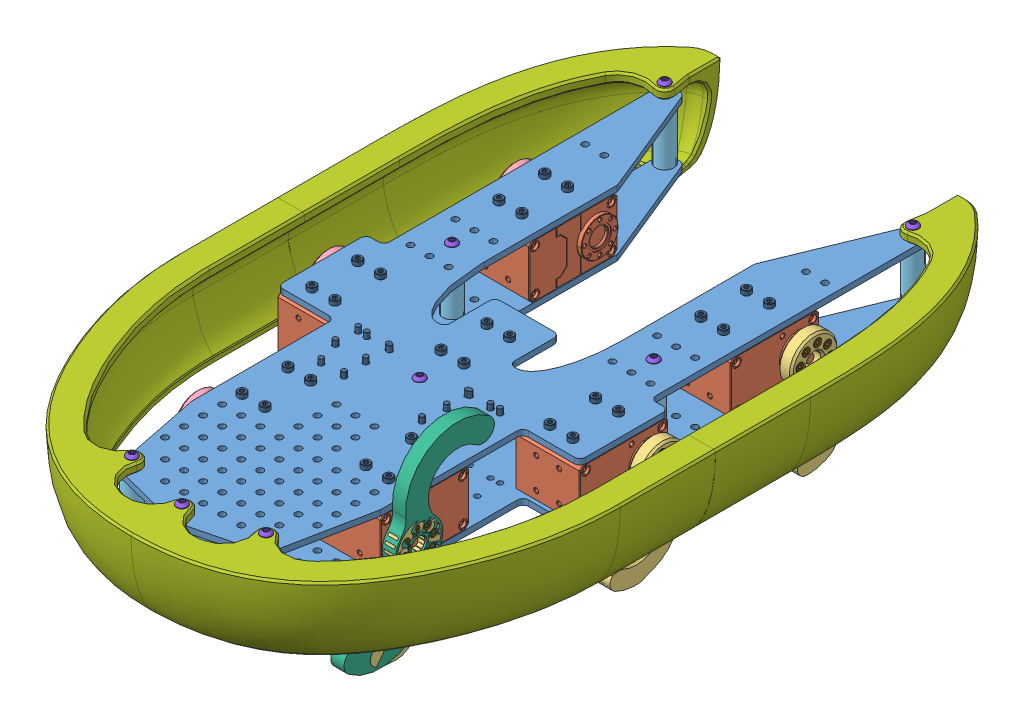
SolidWorks assembly 0100-A-Drive Base Flat, configuration Default. Lengths in mm.
Overall size (299.55 79.42 397.77).
179 component instances, 12 part files, 60 mates.
Components (placement in the parent):
- 0100-P-01-Frame Flat-2: 0100-P-01-Frame Flat [Default] at origin size (168 3.15 328.59)
- DYNAMIXEL XM,H-430-1: DYNAMIXEL XM,H-430 [Default] at (53 14.25 -88.75) x (0 -1 0) z (1 0 0) size (28.5 46.5 42.4)
- 0100-P-02-Leg-2: 0100-P-02-Leg [Default] at (51.5 14.25 98.75) x (1 0 0) z (0 0.528293 0.849062) size (7.78 62.2 37.5)
- DYNAMIXEL XM,H-430-3: DYNAMIXEL XM,H-430 [Default] at (62.5 14.25 0) x (0 -1 0) z (1 0 0) size (28.5 46.5 42.4)
- 0100-P-02-Leg-3: 0100-P-02-Leg [Default] at (81.5 14.25 0) x (1 0 0) z (0 0.588908 0.8082) size (7.78 62.2 37.5)
- DYNAMIXEL XM,H-430-4: DYNAMIXEL XM,H-430 [Default] at (-53 14.25 -88.75) x (0 1 0) z (-1 0 0) size (28.5 46.5 42.4)
- Mirror0100-P-02-Leg-4: Mirror0100-P-02-Leg [Default] at (-81.5 14.25 0) x (-1 0 0) z (0 -0.588908 -0.8082) size (7.78 62.2 37.5)
- DYNAMIXEL XM,H-430-6: DYNAMIXEL XM,H-430 [Default] at (-62.5 14.25 0) x (0 1 0) z (-1 0 0) size (28.5 46.5 42.4)
- Mirror0100-P-02-Leg-5: Mirror0100-P-02-Leg [Default] at (-51.5 14.25 98.75) x (-1 0 0) z (0 -0.528293 -0.849062) size (7.78 62.2 37.5)
- 0100-P-02-Leg-8: 0100-P-02-Leg [Default] at (72 14.25 -88.75) x (1 0 0) z (0 0.172625 0.984988) size (7.78 62.2 37.5)
- Mirror0100-P-02-Leg-9: Mirror0100-P-02-Leg [Default] at (-72 14.25 -88.75) x (-1 0 0) z (0 -0.172625 -0.984988) size (7.78 62.2 37.5)
- DYNAMIXEL XM,H-430-7: DYNAMIXEL XM,H-430 [Default] at (32.5 14.25 98.75) x (0 1 0) z (1 0 0) size (28.5 46.5 42.4)
- DYNAMIXEL XM,H-430-8: DYNAMIXEL XM,H-430 [Default] at (-32.5 14.25 98.75) x (0 -1 0) z (-1 0 0) size (28.5 46.5 42.4)
- 0100-P-01-Frame Flat-3: 0100-P-01-Frame Flat [Default] at (0 31.5 0) size (168 3.15 328.59)
- 0100-P-03-Frame Spacer-1: 0100-P-03-Frame Spacer [Default] at (0 14.25 164.8423) size (9.53 28.5 9.53)
- 0100-P-03-Frame Spacer-4: 0100-P-03-Frame Spacer [Default] at (-53 14.25 -30) size (9.53 28.5 9.53)
- 0100-P-03-Frame Spacer-5: 0100-P-03-Frame Spacer [Default] at (53 14.25 -30) size (9.53 28.5 9.53)
- 0100-P-03-Frame Spacer-8: 0100-P-03-Frame Spacer [Default] at (0 14.25 39.9478) size (9.53 28.5 9.53)
- 0100-P-02-Leg S-1: 0100-P-02-Leg S [Default] at (51.5 14.25 98.75) x (1 0 0) z (0 -0.739993 -0.672614) size (7 109.35 55) (hidden)
- 0100-P-03-Frame Spacer-9: 0100-P-03-Frame Spacer [Default] at (-35.2156 14.25 155.9269) size (9.53 28.5 9.53)
- 0100-P-03-Frame Spacer-10: 0100-P-03-Frame Spacer [Default] at (35.2156 14.25 155.9269) size (9.53 28.5 9.53)
- part1^0100-a-drive base flat-1: part1^0100-a-drive base flat [Default] at origin (suppressed, hidden, virtual)
- 0100-P-03-Frame Spacer-11: 0100-P-03-Frame Spacer [Default] at (-65.2375 14.25 -153.9875) size (9.53 28.5 9.53)
- 0100-P-03-Frame Spacer-12: 0100-P-03-Frame Spacer [Default] at (65.2375 14.25 -153.9875) size (9.53 28.5 9.53)
- 0100-P-04-Bottom Shell-1: 0100-P-04-Bottom Shell [Default] at origin size (299.55 50.12 397.77)
- 92095A168_Button Head Hex Drive Screw-1: 92095A168_Button Head Hex Drive Screw [92095A168] at (35.2156 -8.4212 155.9269) x (-0.18378 0 0.982967) z (0 -1 0) size (5.7 5.7 15.77)
- 92095A168_Button Head Hex Drive Screw-3: 92095A168_Button Head Hex Drive Screw [92095A168] at (0 -8.4212 164.8423) x (-0.18378 0 0.982967) z (0 -1 0) size (5.7 5.7 15.77)
- 92095A168_Button Head Hex Drive Screw-8: 92095A168_Button Head Hex Drive Screw [92095A168] at (0 38.15 164.8423) x (0.861075 0 -0.508478) z (0 1 0) size (5.7 5.7 15.77)
- 92095A168_Button Head Hex Drive Screw-18: 92095A168_Button Head Hex Drive Screw [92095A168] at (65.2375 -8.4212 -153.9875) x (0.722393 0 0.691483) z (0 -1 0) size (5.7 5.7 15.77)
- 92095A168_Button Head Hex Drive Screw-22: 92095A168_Button Head Hex Drive Screw [92095A168] at (35.2156 38.15 155.9269) x (0.749821 0 -0.661641) z (0 1 0) size (5.7 5.7 15.77)
- 92095A168_Button Head Hex Drive Screw-25: 92095A168_Button Head Hex Drive Screw [92095A168] at (65.2375 38.15 -153.9875) x (0.152162 0 -0.988356) z (0 1 0) size (5.7 5.7 15.77)
- 92095A168_Button Head Hex Drive Screw-28: 92095A168_Button Head Hex Drive Screw [92095A168] at (0 33.15 39.9478) x (0.426776 0 -0.904358) z (0 1 0) size (5.7 5.7 15.77)
- 92095A168_Button Head Hex Drive Screw-32: 92095A168_Button Head Hex Drive Screw [92095A168] at (53 33.15 -30) x (0.248698 0 -0.968581) z (0 1 0) size (5.7 5.7 15.77)
- 92095A168_Button Head Hex Drive Screw-34: 92095A168_Button Head Hex Drive Screw [92095A168] at (0 -4.65 39.9478) x (0.231386 0 0.972862) z (0 -1 0) size (5.7 5.7 15.77)
- 92095A168_Button Head Hex Drive Screw-36: 92095A168_Button Head Hex Drive Screw [92095A168] at (53 -4.65 -30) x (-0.704193 0 0.710008) z (0 -1 0) size (5.7 5.7 15.77)
- 92095A168_Button Head Hex Drive Screw-38: 92095A168_Button Head Hex Drive Screw [92095A168] at (-53 33.15 -30) x (0.248698 0 0.968581) z (0 1 0) size (5.7 5.7 15.77)
- 92095A168_Button Head Hex Drive Screw-39: 92095A168_Button Head Hex Drive Screw [92095A168] at (-65.2375 38.15 -153.9875) x (0.152162 0 0.988356) z (0 1 0) size (5.7 5.7 15.77)
- 92095A168_Button Head Hex Drive Screw-40: 92095A168_Button Head Hex Drive Screw [92095A168] at (-65.2375 -8.4212 -153.9875) x (-0.722393 0 0.691483) z (0 -1 0) size (5.7 5.7 15.77)
- 92095A168_Button Head Hex Drive Screw-41: 92095A168_Button Head Hex Drive Screw [92095A168] at (0 -4.65 39.9478) x (0.231386 0 -0.972862) z (0 -1 0) size (5.7 5.7 15.77)
- 92095A168_Button Head Hex Drive Screw-42: 92095A168_Button Head Hex Drive Screw [92095A168] at (-53 -4.65 -30) x (-0.704193 0 -0.710008) z (0 -1 0) size (5.7 5.7 15.77)
- 92095A168_Button Head Hex Drive Screw-43: 92095A168_Button Head Hex Drive Screw [92095A168] at (-35.2156 -8.4212 155.9269) x (-0.18378 0 -0.982967) z (0 -1 0) size (5.7 5.7 15.77)
- 92095A168_Button Head Hex Drive Screw-44: 92095A168_Button Head Hex Drive Screw [92095A168] at (-35.2156 38.15 155.9269) x (-0.749821 0 -0.661641) z (0 1 0) size (5.7 5.7 15.77)
- 91292A832_TYPE 18-8 SS SOCKET HEAD CAP SCREW-1: 91292A832_TYPE 18-8 SS SOCKET HEAD CAP SCREW [91292A832] at (48.5 22.0415 100.5645) x (0 0 1) z (-1 0 0) size (3.8 3.8 10.09)
- 91292A832_TYPE 18-8 SS SOCKET HEAD CAP SCREW-2: 91292A832_TYPE 18-8 SS SOCKET HEAD CAP SCREW [91292A832] at (48.5 21.0425 94.5237) x (0 0 1) z (-1 0 0) size (3.8 3.8 10.09)
- 91292A832_TYPE 18-8 SS SOCKET HEAD CAP SCREW-3: 91292A832_TYPE 18-8 SS SOCKET HEAD CAP SCREW [91292A832] at (48.5 18.4763 105.5425) x (0 0 1) z (-1 0 0) size (3.8 3.8 10.09)
- 91292A832_TYPE 18-8 SS SOCKET HEAD CAP SCREW-4: 91292A832_TYPE 18-8 SS SOCKET HEAD CAP SCREW [91292A832] at (48.5 12.4355 106.5415) x (0 0 1) z (-1 0 0) size (3.8 3.8 10.09)
- 91292A832_TYPE 18-8 SS SOCKET HEAD CAP SCREW-5: 91292A832_TYPE 18-8 SS SOCKET HEAD CAP SCREW [91292A832] at (48.5 7.4575 102.9763) x (0 0 1) z (-1 0 0) size (3.8 3.8 10.09)
- 91292A832_TYPE 18-8 SS SOCKET HEAD CAP SCREW-6: 91292A832_TYPE 18-8 SS SOCKET HEAD CAP SCREW [91292A832] at (48.5 6.4585 96.9355) x (0 0 1) z (-1 0 0) size (3.8 3.8 10.09)
- 91292A832_TYPE 18-8 SS SOCKET HEAD CAP SCREW-7: 91292A832_TYPE 18-8 SS SOCKET HEAD CAP SCREW [91292A832] at (48.5 10.0237 91.9575) x (0 0 1) z (-1 0 0) size (3.8 3.8 10.09)
- 91292A832_TYPE 18-8 SS SOCKET HEAD CAP SCREW-8: 91292A832_TYPE 18-8 SS SOCKET HEAD CAP SCREW [91292A832] at (48.5 16.0645 90.9585) x (0 0 1) z (-1 0 0) size (3.8 3.8 10.09)
- 91292A832_TYPE 18-8 SS SOCKET HEAD CAP SCREW-9: 91292A832_TYPE 18-8 SS SOCKET HEAD CAP SCREW [91292A832] at (78.5 22.1532 1.2405) x (0 -0.158553 0.987351) z (-1 0 0) size (3.8 3.8 10.09)
- 91292A832_TYPE 18-8 SS SOCKET HEAD CAP SCREW-11: 91292A832_TYPE 18-8 SS SOCKET HEAD CAP SCREW [91292A832] at (69 20.7984 -84.1546) x (0 -0.282984 0.959125) z (-1 0 0) size (3.8 3.8 10.09)
- 91292A832_TYPE 18-8 SS SOCKET HEAD CAP SCREW-13: 91292A832_TYPE 18-8 SS SOCKET HEAD CAP SCREW [91292A832] at (78.5 20.7156 -4.7113) x (0 -0.158553 0.987351) z (-1 0 0) size (3.8 3.8 10.09)
- 91292A832_TYPE 18-8 SS SOCKET HEAD CAP SCREW-14: 91292A832_TYPE 18-8 SS SOCKET HEAD CAP SCREW [91292A832] at (78.5 18.9613 6.4656) x (0 -0.158553 0.987351) z (-1 0 0) size (3.8 3.8 10.09)
- 91292A832_TYPE 18-8 SS SOCKET HEAD CAP SCREW-15: 91292A832_TYPE 18-8 SS SOCKET HEAD CAP SCREW [91292A832] at (78.5 13.0095 7.9032) x (0 -0.158553 0.987351) z (-1 0 0) size (3.8 3.8 10.09)
- 91292A832_TYPE 18-8 SS SOCKET HEAD CAP SCREW-16: 91292A832_TYPE 18-8 SS SOCKET HEAD CAP SCREW [91292A832] at (78.5 7.7844 4.7113) x (0 -0.158553 0.987351) z (-1 0 0) size (3.8 3.8 10.09)
- 91292A832_TYPE 18-8 SS SOCKET HEAD CAP SCREW-17: 91292A832_TYPE 18-8 SS SOCKET HEAD CAP SCREW [91292A832] at (78.5 6.3468 -1.2405) x (0 -0.158553 0.987351) z (-1 0 0) size (3.8 3.8 10.09)
- 91292A832_TYPE 18-8 SS SOCKET HEAD CAP SCREW-18: 91292A832_TYPE 18-8 SS SOCKET HEAD CAP SCREW [91292A832] at (78.5 9.5387 -6.4656) x (0 -0.158553 0.987351) z (-1 0 0) size (3.8 3.8 10.09)
- 91292A832_TYPE 18-8 SS SOCKET HEAD CAP SCREW-19: 91292A832_TYPE 18-8 SS SOCKET HEAD CAP SCREW [91292A832] at (78.5 15.4905 -7.9032) x (0 -0.158553 0.987351) z (-1 0 0) size (3.8 3.8 10.09)
- 91292A832_TYPE 18-8 SS SOCKET HEAD CAP SCREW-20: 91292A832_TYPE 18-8 SS SOCKET HEAD CAP SCREW [91292A832] at (69 22.1299 -90.131) x (0 -0.282984 0.959125) z (-1 0 0) size (3.8 3.8 10.09)
- 91292A832_TYPE 18-8 SS SOCKET HEAD CAP SCREW-21: 91292A832_TYPE 18-8 SS SOCKET HEAD CAP SCREW [91292A832] at (69 15.631 -80.8701) x (0 -0.282984 0.959125) z (-1 0 0) size (3.8 3.8 10.09)
- 91292A832_TYPE 18-8 SS SOCKET HEAD CAP SCREW-22: 91292A832_TYPE 18-8 SS SOCKET HEAD CAP SCREW [91292A832] at (69 9.6546 -82.2016) x (0 -0.282984 0.959125) z (-1 0 0) size (3.8 3.8 10.09)
- 91292A832_TYPE 18-8 SS SOCKET HEAD CAP SCREW-23: 91292A832_TYPE 18-8 SS SOCKET HEAD CAP SCREW [91292A832] at (69 6.3701 -87.369) x (0 -0.282984 0.959125) z (-1 0 0) size (3.8 3.8 10.09)
- 91292A832_TYPE 18-8 SS SOCKET HEAD CAP SCREW-24: 91292A832_TYPE 18-8 SS SOCKET HEAD CAP SCREW [91292A832] at (69 7.7016 -93.3454) x (0 -0.282984 0.959125) z (-1 0 0) size (3.8 3.8 10.09)
- 91292A832_TYPE 18-8 SS SOCKET HEAD CAP SCREW-25: 91292A832_TYPE 18-8 SS SOCKET HEAD CAP SCREW [91292A832] at (69 12.869 -96.6299) x (0 -0.282984 0.959125) z (-1 0 0) size (3.8 3.8 10.09)
- 91292A832_TYPE 18-8 SS SOCKET HEAD CAP SCREW-26: 91292A832_TYPE 18-8 SS SOCKET HEAD CAP SCREW [91292A832] at (69 18.8454 -95.2984) x (0 -0.282984 0.959125) z (-1 0 0) size (3.8 3.8 10.09)
- 91292A832_TYPE 18-8 SS SOCKET HEAD CAP SCREW-27: 91292A832_TYPE 18-8 SS SOCKET HEAD CAP SCREW [91292A832] at (-48.5 18.4763 105.5425) x (0 0 -1) z (1 0 0) size (3.8 3.8 10.09)
- 91292A832_TYPE 18-8 SS SOCKET HEAD CAP SCREW-28: 91292A832_TYPE 18-8 SS SOCKET HEAD CAP SCREW [91292A832] at (-48.5 22.0415 100.5645) x (0 0 -1) z (1 0 0) size (3.8 3.8 10.09)
- 91292A832_TYPE 18-8 SS SOCKET HEAD CAP SCREW-29: 91292A832_TYPE 18-8 SS SOCKET HEAD CAP SCREW [91292A832] at (-48.5 21.0425 94.5237) x (0 0 -1) z (1 0 0) size (3.8 3.8 10.09)
- 91292A832_TYPE 18-8 SS SOCKET HEAD CAP SCREW-30: 91292A832_TYPE 18-8 SS SOCKET HEAD CAP SCREW [91292A832] at (-48.5 16.0645 90.9585) x (0 0 -1) z (1 0 0) size (3.8 3.8 10.09)
- 91292A832_TYPE 18-8 SS SOCKET HEAD CAP SCREW-31: 91292A832_TYPE 18-8 SS SOCKET HEAD CAP SCREW [91292A832] at (-48.5 10.0237 91.9575) x (0 0 -1) z (1 0 0) size (3.8 3.8 10.09)
- 91292A832_TYPE 18-8 SS SOCKET HEAD CAP SCREW-32: 91292A832_TYPE 18-8 SS SOCKET HEAD CAP SCREW [91292A832] at (-48.5 6.4585 96.9355) x (0 0 -1) z (1 0 0) size (3.8 3.8 10.09)
- 91292A832_TYPE 18-8 SS SOCKET HEAD CAP SCREW-33: 91292A832_TYPE 18-8 SS SOCKET HEAD CAP SCREW [91292A832] at (-48.5 7.4575 102.9763) x (0 0 -1) z (1 0 0) size (3.8 3.8 10.09)
- 91292A832_TYPE 18-8 SS SOCKET HEAD CAP SCREW-34: 91292A832_TYPE 18-8 SS SOCKET HEAD CAP SCREW [91292A832] at (-48.5 12.4355 106.5415) x (0 0 -1) z (1 0 0) size (3.8 3.8 10.09)
- 0100-P-03-Frame Spacer-13: 0100-P-03-Frame Spacer [Default] at (-35.2156 14.25 155.9269) x (-1 0 0) z (0 0 -1) size (9.53 28.5 9.53)
- 91292A832_TYPE 18-8 SS SOCKET HEAD CAP SCREW-35: 91292A832_TYPE 18-8 SS SOCKET HEAD CAP SCREW [91292A832] at (-78.5 22.1532 1.2405) x (0 0.158553 -0.987351) z (1 0 0) size (3.8 3.8 10.09)
- 91292A832_TYPE 18-8 SS SOCKET HEAD CAP SCREW-36: 91292A832_TYPE 18-8 SS SOCKET HEAD CAP SCREW [91292A832] at (-78.5 20.7156 -4.7113) x (0 0.158553 -0.987351) z (1 0 0) size (3.8 3.8 10.09)
- 91292A832_TYPE 18-8 SS SOCKET HEAD CAP SCREW-37: 91292A832_TYPE 18-8 SS SOCKET HEAD CAP SCREW [91292A832] at (-78.5 18.9613 6.4656) x (0 0.158553 -0.987351) z (1 0 0) size (3.8 3.8 10.09)
- 91292A832_TYPE 18-8 SS SOCKET HEAD CAP SCREW-38: 91292A832_TYPE 18-8 SS SOCKET HEAD CAP SCREW [91292A832] at (-78.5 13.0095 7.9032) x (0 0.158553 -0.987351) z (1 0 0) size (3.8 3.8 10.09)
- 91292A832_TYPE 18-8 SS SOCKET HEAD CAP SCREW-39: 91292A832_TYPE 18-8 SS SOCKET HEAD CAP SCREW [91292A832] at (-78.5 7.7844 4.7113) x (0 0.158553 -0.987351) z (1 0 0) size (3.8 3.8 10.09)
- 91292A832_TYPE 18-8 SS SOCKET HEAD CAP SCREW-40: 91292A832_TYPE 18-8 SS SOCKET HEAD CAP SCREW [91292A832] at (-78.5 6.3468 -1.2405) x (0 0.158553 -0.987351) z (1 0 0) size (3.8 3.8 10.09)
- 91292A832_TYPE 18-8 SS SOCKET HEAD CAP SCREW-41: 91292A832_TYPE 18-8 SS SOCKET HEAD CAP SCREW [91292A832] at (-78.5 9.5387 -6.4656) x (0 0.158553 -0.987351) z (1 0 0) size (3.8 3.8 10.09)
- 91292A832_TYPE 18-8 SS SOCKET HEAD CAP SCREW-42: 91292A832_TYPE 18-8 SS SOCKET HEAD CAP SCREW [91292A832] at (-78.5 15.4905 -7.9032) x (0 0.158553 -0.987351) z (1 0 0) size (3.8 3.8 10.09)
- 91292A832_TYPE 18-8 SS SOCKET HEAD CAP SCREW-43: 91292A832_TYPE 18-8 SS SOCKET HEAD CAP SCREW [91292A832] at (-69 20.7984 -84.1546) x (0 0.282984 -0.959125) z (1 0 0) size (3.8 3.8 10.09)
- 91292A832_TYPE 18-8 SS SOCKET HEAD CAP SCREW-44: 91292A832_TYPE 18-8 SS SOCKET HEAD CAP SCREW [91292A832] at (-69 22.1299 -90.131) x (0 0.282984 -0.959125) z (1 0 0) size (3.8 3.8 10.09)
- 91292A832_TYPE 18-8 SS SOCKET HEAD CAP SCREW-45: 91292A832_TYPE 18-8 SS SOCKET HEAD CAP SCREW [91292A832] at (-69 15.631 -80.8701) x (0 0.282984 -0.959125) z (1 0 0) size (3.8 3.8 10.09)
- 91292A832_TYPE 18-8 SS SOCKET HEAD CAP SCREW-46: 91292A832_TYPE 18-8 SS SOCKET HEAD CAP SCREW [91292A832] at (-69 9.6546 -82.2016) x (0 0.282984 -0.959125) z (1 0 0) size (3.8 3.8 10.09)
- 91292A832_TYPE 18-8 SS SOCKET HEAD CAP SCREW-47: 91292A832_TYPE 18-8 SS SOCKET HEAD CAP SCREW [91292A832] at (-69 6.3701 -87.369) x (0 0.282984 -0.959125) z (1 0 0) size (3.8 3.8 10.09)
- 91292A832_TYPE 18-8 SS SOCKET HEAD CAP SCREW-48: 91292A832_TYPE 18-8 SS SOCKET HEAD CAP SCREW [91292A832] at (-69 7.7016 -93.3454) x (0 0.282984 -0.959125) z (1 0 0) size (3.8 3.8 10.09)
- 91292A832_TYPE 18-8 SS SOCKET HEAD CAP SCREW-49: 91292A832_TYPE 18-8 SS SOCKET HEAD CAP SCREW [91292A832] at (-69 12.869 -96.6299) x (0 0.282984 -0.959125) z (1 0 0) size (3.8 3.8 10.09)
- 91292A832_TYPE 18-8 SS SOCKET HEAD CAP SCREW-50: 91292A832_TYPE 18-8 SS SOCKET HEAD CAP SCREW [91292A832] at (-69 18.8454 -95.2984) x (0 0.282984 -0.959125) z (1 0 0) size (3.8 3.8 10.09)
- 91292A010_TYPE 18-8 SS SOCKET HEAD CAP SCREW-1: 91292A010_TYPE 18-8 SS SOCKET HEAD CAP SCREW [91292A010] at (38.5 25.5 94.75) x (0.850387 0 0.526158) z (0 -1 0) size (4.5 4.5 8.62)
- 91292A010_TYPE 18-8 SS SOCKET HEAD CAP SCREW-2: 91292A010_TYPE 18-8 SS SOCKET HEAD CAP SCREW [91292A010] at (68.5 25.5 28) x (0.850387 0 0.526158) z (0 -1 0) size (4.5 4.5 8.62)
- 91292A010_TYPE 18-8 SS SOCKET HEAD CAP SCREW-3: 91292A010_TYPE 18-8 SS SOCKET HEAD CAP SCREW [91292A010] at (56.5 25.5 28) x (0.850387 0 0.526158) z (0 -1 0) size (4.5 4.5 8.62)
- 91292A010_TYPE 18-8 SS SOCKET HEAD CAP SCREW-4: 91292A010_TYPE 18-8 SS SOCKET HEAD CAP SCREW [91292A010] at (56.5 25.5 4) x (0.850387 0 0.526158) z (0 -1 0) size (4.5 4.5 8.62)
- 91292A010_TYPE 18-8 SS SOCKET HEAD CAP SCREW-5: 91292A010_TYPE 18-8 SS SOCKET HEAD CAP SCREW [91292A010] at (68.5 25.5 4) x (0.850387 0 0.526158) z (0 -1 0) size (4.5 4.5 8.62)
- 91292A010_TYPE 18-8 SS SOCKET HEAD CAP SCREW-6: 91292A010_TYPE 18-8 SS SOCKET HEAD CAP SCREW [91292A010] at (6 25.5 -1.3022) x (0.850387 0 0.526158) z (0 -1 0) size (4.5 4.5 8.62)
- 91292A010_TYPE 18-8 SS SOCKET HEAD CAP SCREW-7: 91292A010_TYPE 18-8 SS SOCKET HEAD CAP SCREW [91292A010] at (6 25.5 22.6978) x (0.850387 0 0.526158) z (0 -1 0) size (4.5 4.5 8.62)
- 91292A010_TYPE 18-8 SS SOCKET HEAD CAP SCREW-8: 91292A010_TYPE 18-8 SS SOCKET HEAD CAP SCREW [91292A010] at (59 25.5 -60.75) x (0.850387 0 0.526158) z (0 -1 0) size (4.5 4.5 8.62)
- 91292A010_TYPE 18-8 SS SOCKET HEAD CAP SCREW-9: 91292A010_TYPE 18-8 SS SOCKET HEAD CAP SCREW [91292A010] at (47 25.5 -60.75) x (0.850387 0 0.526158) z (0 -1 0) size (4.5 4.5 8.62)
- 91292A010_TYPE 18-8 SS SOCKET HEAD CAP SCREW-10: 91292A010_TYPE 18-8 SS SOCKET HEAD CAP SCREW [91292A010] at (47 25.5 -84.75) x (0.850387 0 0.526158) z (0 -1 0) size (4.5 4.5 8.62)
- 91292A010_TYPE 18-8 SS SOCKET HEAD CAP SCREW-11: 91292A010_TYPE 18-8 SS SOCKET HEAD CAP SCREW [91292A010] at (59 25.5 -84.75) x (0.850387 0 0.526158) z (0 -1 0) size (4.5 4.5 8.62)
- 91292A010_TYPE 18-8 SS SOCKET HEAD CAP SCREW-12: 91292A010_TYPE 18-8 SS SOCKET HEAD CAP SCREW [91292A010] at (26.5 25.5 70.75) x (0.850387 0 0.526158) z (0 -1 0) size (4.5 4.5 8.62)
- 91292A010_TYPE 18-8 SS SOCKET HEAD CAP SCREW-13: 91292A010_TYPE 18-8 SS SOCKET HEAD CAP SCREW [91292A010] at (38.5 25.5 70.75) x (0.850387 0 0.526158) z (0 -1 0) size (4.5 4.5 8.62)
- 91292A010_TYPE 18-8 SS SOCKET HEAD CAP SCREW-14: 91292A010_TYPE 18-8 SS SOCKET HEAD CAP SCREW [91292A010] at (26.5 25.5 94.75) x (0.850387 0 0.526158) z (0 -1 0) size (4.5 4.5 8.62)
- 91292A010_TYPE 18-8 SS SOCKET HEAD CAP SCREW-16: 91292A010_TYPE 18-8 SS SOCKET HEAD CAP SCREW [91292A010] at (38.5 3 94.75) x (0.977142 0 0.212587) z (0 1 0) size (4.5 4.5 8.62)
- 91292A010_TYPE 18-8 SS SOCKET HEAD CAP SCREW-18: 91292A010_TYPE 18-8 SS SOCKET HEAD CAP SCREW [91292A010] at (68.5 3 28) x (0.977142 0 0.212587) z (0 1 0) size (4.5 4.5 8.62)
- 91292A010_TYPE 18-8 SS SOCKET HEAD CAP SCREW-19: 91292A010_TYPE 18-8 SS SOCKET HEAD CAP SCREW [91292A010] at (56.5 3 28) x (0.977142 0 0.212587) z (0 1 0) size (4.5 4.5 8.62)
- 91292A010_TYPE 18-8 SS SOCKET HEAD CAP SCREW-20: 91292A010_TYPE 18-8 SS SOCKET HEAD CAP SCREW [91292A010] at (56.5 3 4) x (0.977142 0 0.212587) z (0 1 0) size (4.5 4.5 8.62)
- 91292A010_TYPE 18-8 SS SOCKET HEAD CAP SCREW-21: 91292A010_TYPE 18-8 SS SOCKET HEAD CAP SCREW [91292A010] at (68.5 3 4) x (0.977142 0 0.212587) z (0 1 0) size (4.5 4.5 8.62)
- 91292A010_TYPE 18-8 SS SOCKET HEAD CAP SCREW-22: 91292A010_TYPE 18-8 SS SOCKET HEAD CAP SCREW [91292A010] at (6 3 -1.3022) x (0.977142 0 0.212587) z (0 1 0) size (4.5 4.5 8.62)
- 91292A010_TYPE 18-8 SS SOCKET HEAD CAP SCREW-23: 91292A010_TYPE 18-8 SS SOCKET HEAD CAP SCREW [91292A010] at (6 3 22.6978) x (0.977142 0 0.212587) z (0 1 0) size (4.5 4.5 8.62)
- 91292A010_TYPE 18-8 SS SOCKET HEAD CAP SCREW-24: 91292A010_TYPE 18-8 SS SOCKET HEAD CAP SCREW [91292A010] at (59 3 -60.75) x (0.977142 0 0.212587) z (0 1 0) size (4.5 4.5 8.62)
- 91292A010_TYPE 18-8 SS SOCKET HEAD CAP SCREW-25: 91292A010_TYPE 18-8 SS SOCKET HEAD CAP SCREW [91292A010] at (47 3 -60.75) x (0.977142 0 0.212587) z (0 1 0) size (4.5 4.5 8.62)
- 91292A010_TYPE 18-8 SS SOCKET HEAD CAP SCREW-26: 91292A010_TYPE 18-8 SS SOCKET HEAD CAP SCREW [91292A010] at (47 3 -84.75) x (0.977142 0 0.212587) z (0 1 0) size (4.5 4.5 8.62)
- 91292A010_TYPE 18-8 SS SOCKET HEAD CAP SCREW-27: 91292A010_TYPE 18-8 SS SOCKET HEAD CAP SCREW [91292A010] at (59 3 -84.75) x (0.977142 0 0.212587) z (0 1 0) size (4.5 4.5 8.62)
- 91292A010_TYPE 18-8 SS SOCKET HEAD CAP SCREW-28: 91292A010_TYPE 18-8 SS SOCKET HEAD CAP SCREW [91292A010] at (26.5 3 70.75) x (0.977142 0 0.212587) z (0 1 0) size (4.5 4.5 8.62)
- 91292A010_TYPE 18-8 SS SOCKET HEAD CAP SCREW-29: 91292A010_TYPE 18-8 SS SOCKET HEAD CAP SCREW [91292A010] at (38.5 3 70.75) x (0.977142 0 0.212587) z (0 1 0) size (4.5 4.5 8.62)
- 91292A010_TYPE 18-8 SS SOCKET HEAD CAP SCREW-30: 91292A010_TYPE 18-8 SS SOCKET HEAD CAP SCREW [91292A010] at (26.5 3 94.75) x (0.977142 0 0.212587) z (0 1 0) size (4.5 4.5 8.62)
- 91292A010_TYPE 18-8 SS SOCKET HEAD CAP SCREW-31: 91292A010_TYPE 18-8 SS SOCKET HEAD CAP SCREW [91292A010] at (-38.5 3 94.75) x (-0.977142 0 0.212587) z (0 1 0) size (4.5 4.5 8.62)
- 91292A010_TYPE 18-8 SS SOCKET HEAD CAP SCREW-32: 91292A010_TYPE 18-8 SS SOCKET HEAD CAP SCREW [91292A010] at (-26.5 3 94.75) x (-0.977142 0 0.212587) z (0 1 0) size (4.5 4.5 8.62)
- 91292A010_TYPE 18-8 SS SOCKET HEAD CAP SCREW-33: 91292A010_TYPE 18-8 SS SOCKET HEAD CAP SCREW [91292A010] at (-38.5 3 70.75) x (-0.977142 0 0.212587) z (0 1 0) size (4.5 4.5 8.62)
- 91292A010_TYPE 18-8 SS SOCKET HEAD CAP SCREW-34: 91292A010_TYPE 18-8 SS SOCKET HEAD CAP SCREW [91292A010] at (-26.5 3 70.75) x (-0.977142 0 0.212587) z (0 1 0) size (4.5 4.5 8.62)
- 91292A010_TYPE 18-8 SS SOCKET HEAD CAP SCREW-35: 91292A010_TYPE 18-8 SS SOCKET HEAD CAP SCREW [91292A010] at (-56.5 3 4) x (-0.977142 0 0.212587) z (0 1 0) size (4.5 4.5 8.62)
- 91292A010_TYPE 18-8 SS SOCKET HEAD CAP SCREW-36: 91292A010_TYPE 18-8 SS SOCKET HEAD CAP SCREW [91292A010] at (-68.5 3 4) x (-0.977142 0 0.212587) z (0 1 0) size (4.5 4.5 8.62)
- 91292A010_TYPE 18-8 SS SOCKET HEAD CAP SCREW-37: 91292A010_TYPE 18-8 SS SOCKET HEAD CAP SCREW [91292A010] at (-68.5 3 28) x (-0.977142 0 0.212587) z (0 1 0) size (4.5 4.5 8.62)
- 91292A010_TYPE 18-8 SS SOCKET HEAD CAP SCREW-38: 91292A010_TYPE 18-8 SS SOCKET HEAD CAP SCREW [91292A010] at (-56.5 3 28) x (-0.977142 0 0.212587) z (0 1 0) size (4.5 4.5 8.62)
- 91292A010_TYPE 18-8 SS SOCKET HEAD CAP SCREW-39: 91292A010_TYPE 18-8 SS SOCKET HEAD CAP SCREW [91292A010] at (-6 3 22.6978) x (-0.977142 0 0.212587) z (0 1 0) size (4.5 4.5 8.62)
- 91292A010_TYPE 18-8 SS SOCKET HEAD CAP SCREW-40: 91292A010_TYPE 18-8 SS SOCKET HEAD CAP SCREW [91292A010] at (-6 3 -1.3022) x (-0.977142 0 0.212587) z (0 1 0) size (4.5 4.5 8.62)
- 91292A010_TYPE 18-8 SS SOCKET HEAD CAP SCREW-41: 91292A010_TYPE 18-8 SS SOCKET HEAD CAP SCREW [91292A010] at (-59 3 -60.75) x (-0.977142 0 0.212587) z (0 1 0) size (4.5 4.5 8.62)
- 91292A010_TYPE 18-8 SS SOCKET HEAD CAP SCREW-42: 91292A010_TYPE 18-8 SS SOCKET HEAD CAP SCREW [91292A010] at (-47 3 -60.75) x (-0.977142 0 0.212587) z (0 1 0) size (4.5 4.5 8.62)
- 91292A010_TYPE 18-8 SS SOCKET HEAD CAP SCREW-43: 91292A010_TYPE 18-8 SS SOCKET HEAD CAP SCREW [91292A010] at (-47 3 -84.75) x (-0.977142 0 0.212587) z (0 1 0) size (4.5 4.5 8.62)
- 91292A010_TYPE 18-8 SS SOCKET HEAD CAP SCREW-44: 91292A010_TYPE 18-8 SS SOCKET HEAD CAP SCREW [91292A010] at (-59 3 -84.75) x (-0.977142 0 0.212587) z (0 1 0) size (4.5 4.5 8.62)
- 91292A010_TYPE 18-8 SS SOCKET HEAD CAP SCREW-45: 91292A010_TYPE 18-8 SS SOCKET HEAD CAP SCREW [91292A010] at (-47 25.5 -60.75) x (-0.850387 0 0.526158) z (0 -1 0) size (4.5 4.5 8.62)
- 91292A010_TYPE 18-8 SS SOCKET HEAD CAP SCREW-46: 91292A010_TYPE 18-8 SS SOCKET HEAD CAP SCREW [91292A010] at (-59 25.5 -60.75) x (-0.850387 0 0.526158) z (0 -1 0) size (4.5 4.5 8.62)
- 91292A010_TYPE 18-8 SS SOCKET HEAD CAP SCREW-47: 91292A010_TYPE 18-8 SS SOCKET HEAD CAP SCREW [91292A010] at (-47 25.5 -84.75) x (-0.850387 0 0.526158) z (0 -1 0) size (4.5 4.5 8.62)
- 91292A010_TYPE 18-8 SS SOCKET HEAD CAP SCREW-48: 91292A010_TYPE 18-8 SS SOCKET HEAD CAP SCREW [91292A010] at (-59 25.5 -84.75) x (-0.850387 0 0.526158) z (0 -1 0) size (4.5 4.5 8.62)
- 91292A010_TYPE 18-8 SS SOCKET HEAD CAP SCREW-49: 91292A010_TYPE 18-8 SS SOCKET HEAD CAP SCREW [91292A010] at (-56.5 25.5 4) x (-0.850387 0 0.526158) z (0 -1 0) size (4.5 4.5 8.62)
- 91292A010_TYPE 18-8 SS SOCKET HEAD CAP SCREW-50: 91292A010_TYPE 18-8 SS SOCKET HEAD CAP SCREW [91292A010] at (-68.5 25.5 4) x (-0.850387 0 0.526158) z (0 -1 0) size (4.5 4.5 8.62)
- 91292A010_TYPE 18-8 SS SOCKET HEAD CAP SCREW-51: 91292A010_TYPE 18-8 SS SOCKET HEAD CAP SCREW [91292A010] at (-56.5 25.5 28) x (-0.850387 0 0.526158) z (0 -1 0) size (4.5 4.5 8.62)
- 91292A010_TYPE 18-8 SS SOCKET HEAD CAP SCREW-52: 91292A010_TYPE 18-8 SS SOCKET HEAD CAP SCREW [91292A010] at (-68.5 25.5 28) x (-0.850387 0 0.526158) z (0 -1 0) size (4.5 4.5 8.62)
- 91292A010_TYPE 18-8 SS SOCKET HEAD CAP SCREW-53: 91292A010_TYPE 18-8 SS SOCKET HEAD CAP SCREW [91292A010] at (-26.5 25.5 70.75) x (-0.850387 0 0.526158) z (0 -1 0) size (4.5 4.5 8.62)
- 91292A010_TYPE 18-8 SS SOCKET HEAD CAP SCREW-54: 91292A010_TYPE 18-8 SS SOCKET HEAD CAP SCREW [91292A010] at (-38.5 25.5 70.75) x (-0.850387 0 0.526158) z (0 -1 0) size (4.5 4.5 8.62)
- 91292A010_TYPE 18-8 SS SOCKET HEAD CAP SCREW-55: 91292A010_TYPE 18-8 SS SOCKET HEAD CAP SCREW [91292A010] at (-26.5 25.5 94.75) x (-0.850387 0 0.526158) z (0 -1 0) size (4.5 4.5 8.62)
- 91292A010_TYPE 18-8 SS SOCKET HEAD CAP SCREW-56: 91292A010_TYPE 18-8 SS SOCKET HEAD CAP SCREW [91292A010] at (-38.5 25.5 94.75) x (-0.850387 0 0.526158) z (0 -1 0) size (4.5 4.5 8.62)
- 91292A010_TYPE 18-8 SS SOCKET HEAD CAP SCREW-57: 91292A010_TYPE 18-8 SS SOCKET HEAD CAP SCREW [91292A010] at (-6 25.5 22.6978) x (0.850387 0 -0.526158) z (0 -1 0) size (4.5 4.5 8.62)
- 91292A010_TYPE 18-8 SS SOCKET HEAD CAP SCREW-58: 91292A010_TYPE 18-8 SS SOCKET HEAD CAP SCREW [91292A010] at (-6 25.5 -1.3022) x (0.850387 0 -0.526158) z (0 -1 0) size (4.5 4.5 8.62)
- 91292A010_TYPE 18-8 SS SOCKET HEAD CAP SCREW-59: 91292A010_TYPE 18-8 SS SOCKET HEAD CAP SCREW [91292A010] at (32.5 34.5 59.25) x (0.46803 0 0.883712) z (0 1 0) size (4.5 4.5 8.62)
- 91292A010_TYPE 18-8 SS SOCKET HEAD CAP SCREW-60: 91292A010_TYPE 18-8 SS SOCKET HEAD CAP SCREW [91292A010] at (-20.5 34.5 59.25) x (0.46803 0 0.883712) z (0 1 0) size (4.5 4.5 8.62)
- 91292A010_TYPE 18-8 SS SOCKET HEAD CAP SCREW-61: 91292A010_TYPE 18-8 SS SOCKET HEAD CAP SCREW [91292A010] at (-32.5 34.5 59.25) x (0.46803 0 0.883712) z (0 1 0) size (4.5 4.5 8.62)
- 91292A010_TYPE 18-8 SS SOCKET HEAD CAP SCREW-62: 91292A010_TYPE 18-8 SS SOCKET HEAD CAP SCREW [91292A010] at (-32.5 34.5 35.25) x (0.46803 0 0.883712) z (0 1 0) size (4.5 4.5 8.62)
- 91292A010_TYPE 18-8 SS SOCKET HEAD CAP SCREW-63: 91292A010_TYPE 18-8 SS SOCKET HEAD CAP SCREW [91292A010] at (-20.5 34.5 35.25) x (0.46803 0 0.883712) z (0 1 0) size (4.5 4.5 8.62)
- 91292A010_TYPE 18-8 SS SOCKET HEAD CAP SCREW-64: 91292A010_TYPE 18-8 SS SOCKET HEAD CAP SCREW [91292A010] at (32.5 34.5 35.25) x (0.46803 0 0.883712) z (0 1 0) size (4.5 4.5 8.62)
- 91292A010_TYPE 18-8 SS SOCKET HEAD CAP SCREW-65: 91292A010_TYPE 18-8 SS SOCKET HEAD CAP SCREW [91292A010] at (20.5 34.5 35.25) x (0.46803 0 0.883712) z (0 1 0) size (4.5 4.5 8.62)
- 91292A010_TYPE 18-8 SS SOCKET HEAD CAP SCREW-66: 91292A010_TYPE 18-8 SS SOCKET HEAD CAP SCREW [91292A010] at (20.5 34.5 59.25) x (0.46803 0 0.883712) z (0 1 0) size (4.5 4.5 8.62)
- 94180A333_HEAT-SET INSERTS FOR PLASTICS-1: 94180A333_HEAT-SET INSERTS FOR PLASTICS [94180A333] at (0 28.5 164.8423) x (0.992126 0 -0.125243) z (0.125243 0 0.992126) size (5.56 6.75 5.56)
- 94180A333_HEAT-SET INSERTS FOR PLASTICS-2: 94180A333_HEAT-SET INSERTS FOR PLASTICS [94180A333] at (0 0 164.8423) x (0.626399 0 0.779502) z (0.779502 0 -0.626399) size (5.56 6.75 5.56)
- 94180A333_HEAT-SET INSERTS FOR PLASTICS-4: 94180A333_HEAT-SET INSERTS FOR PLASTICS [94180A333] at (-65.2375 0 -153.9875) x (0.626399 0 0.779502) z (0.779502 0 -0.626399) size (5.56 6.75 5.56)
- 94180A333_HEAT-SET INSERTS FOR PLASTICS-5: 94180A333_HEAT-SET INSERTS FOR PLASTICS [94180A333] at (65.2375 0 -153.9875) x (0.626399 0 0.779502) z (0.779502 0 -0.626399) size (5.56 6.75 5.56)
- 94180A333_HEAT-SET INSERTS FOR PLASTICS-6: 94180A333_HEAT-SET INSERTS FOR PLASTICS [94180A333] at (-35.2156 0 155.9269) x (0.626399 0 0.779502) z (0.779502 0 -0.626399) size (5.56 6.75 5.56)
- 94180A333_HEAT-SET INSERTS FOR PLASTICS-7: 94180A333_HEAT-SET INSERTS FOR PLASTICS [94180A333] at (35.2156 0 155.9269) x (0.626399 0 0.779502) z (0.779502 0 -0.626399) size (5.56 6.75 5.56)
- 94180A333_HEAT-SET INSERTS FOR PLASTICS-8: 94180A333_HEAT-SET INSERTS FOR PLASTICS [94180A333] at (-53 0 -30) x (0.626399 0 0.779502) z (0.779502 0 -0.626399) size (5.56 6.75 5.56)
- 94180A333_HEAT-SET INSERTS FOR PLASTICS-9: 94180A333_HEAT-SET INSERTS FOR PLASTICS [94180A333] at (53 0 -30) x (0.626399 0 0.779502) z (0.779502 0 -0.626399) size (5.56 6.75 5.56)
- 94180A333_HEAT-SET INSERTS FOR PLASTICS-10: 94180A333_HEAT-SET INSERTS FOR PLASTICS [94180A333] at (0 0 39.9478) x (0.626399 0 0.779502) z (0.779502 0 -0.626399) size (5.56 6.75 5.56)
- 94180A333_HEAT-SET INSERTS FOR PLASTICS-11: 94180A333_HEAT-SET INSERTS FOR PLASTICS [94180A333] at (-65.2375 28.5 -153.9875) x (0.992126 0 -0.125243) z (0.125243 0 0.992126) size (5.56 6.75 5.56)
- 94180A333_HEAT-SET INSERTS FOR PLASTICS-12: 94180A333_HEAT-SET INSERTS FOR PLASTICS [94180A333] at (65.2375 28.5 -153.9875) x (0.992126 0 -0.125243) z (0.125243 0 0.992126) size (5.56 6.75 5.56)
- 94180A333_HEAT-SET INSERTS FOR PLASTICS-13: 94180A333_HEAT-SET INSERTS FOR PLASTICS [94180A333] at (-35.2156 28.5 155.9269) x (0.992126 0 -0.125243) z (0.125243 0 0.992126) size (5.56 6.75 5.56)
- 94180A333_HEAT-SET INSERTS FOR PLASTICS-14: 94180A333_HEAT-SET INSERTS FOR PLASTICS [94180A333] at (35.2156 28.5 155.9269) x (0.992126 0 -0.125243) z (0.125243 0 0.992126) size (5.56 6.75 5.56)
- 94180A333_HEAT-SET INSERTS FOR PLASTICS-15: 94180A333_HEAT-SET INSERTS FOR PLASTICS [94180A333] at (-53 28.5 -30) x (0.992126 0 -0.125243) z (0.125243 0 0.992126) size (5.56 6.75 5.56)
- 94180A333_HEAT-SET INSERTS FOR PLASTICS-16: 94180A333_HEAT-SET INSERTS FOR PLASTICS [94180A333] at (53 28.5 -30) x (0.992126 0 -0.125243) z (0.125243 0 0.992126) size (5.56 6.75 5.56)
- 94180A333_HEAT-SET INSERTS FOR PLASTICS-17: 94180A333_HEAT-SET INSERTS FOR PLASTICS [94180A333] at (0 28.5 39.9478) x (0.992126 0 -0.125243) z (0.125243 0 0.992126) size (5.56 6.75 5.56)
- 91292A010_TYPE 18-8 SS SOCKET HEAD CAP SCREW-67: 91292A010_TYPE 18-8 SS SOCKET HEAD CAP SCREW [91292A010] at (-21.25 34.5 35) x (0.46803 0 0.883712) z (0 1 0) size (4.5 4.5 8.62)
- 91292A010_TYPE 18-8 SS SOCKET HEAD CAP SCREW-68: 91292A010_TYPE 18-8 SS SOCKET HEAD CAP SCREW [91292A010] at (-37.25 34.5 35) x (0.46803 0 0.883712) z (0 1 0) size (4.5 4.5 8.62)
- 91292A010_TYPE 18-8 SS SOCKET HEAD CAP SCREW-69: 91292A010_TYPE 18-8 SS SOCKET HEAD CAP SCREW [91292A010] at (-37.25 34.5 47) x (0.46803 0 0.883712) z (0 1 0) size (4.5 4.5 8.62)
- 91292A010_TYPE 18-8 SS SOCKET HEAD CAP SCREW-70: 91292A010_TYPE 18-8 SS SOCKET HEAD CAP SCREW [91292A010] at (-21.25 34.5 47) x (0.46803 0 0.883712) z (0 1 0) size (4.5 4.5 8.62)
- 91292A010_TYPE 18-8 SS SOCKET HEAD CAP SCREW-71: 91292A010_TYPE 18-8 SS SOCKET HEAD CAP SCREW [91292A010] at (21.25 34.5 47) x (0.46803 0 0.883712) z (0 1 0) size (4.5 4.5 8.62)
- 91292A010_TYPE 18-8 SS SOCKET HEAD CAP SCREW-72: 91292A010_TYPE 18-8 SS SOCKET HEAD CAP SCREW [91292A010] at (21.25 34.5 35) x (0.46803 0 0.883712) z (0 1 0) size (4.5 4.5 8.62)
- 91292A010_TYPE 18-8 SS SOCKET HEAD CAP SCREW-73: 91292A010_TYPE 18-8 SS SOCKET HEAD CAP SCREW [91292A010] at (37.25 34.5 35) x (0.46803 0 0.883712) z (0 1 0) size (4.5 4.5 8.62)
- 91292A010_TYPE 18-8 SS SOCKET HEAD CAP SCREW-74: 91292A010_TYPE 18-8 SS SOCKET HEAD CAP SCREW [91292A010] at (37.25 34.5 47) x (0.46803 0 0.883712) z (0 1 0) size (4.5 4.5 8.62)
Mates (geometry in assembly coordinates):
- Coincident4: coincident anti-aligned: plane of DYNAMIXEL XM,H-430-1 through (36 0 -53.5) normal (0 -1 0)
- Coincident10: coincident: line of 0100-P-01-Frame Flat-2 through (70 0 -100) axis (0 0 1); plane of DYNAMIXEL XM,H-430-1 through (70 14.25 -88.75) normal (1 0 0)
- Coincident12: coincident aligned: plane of 0100-P-01-Frame Flat-2 through (79.5 0 0) normal (1 0 0); plane of DYNAMIXEL XM,H-430-3 through (79.5 14.25 0) normal (1 0 0)
- Concentric3: concentric aligned: cylinder of DYNAMIXEL XM,H-430-3 through (83.85 14.25 0) axis (-1 0 0) radius 4; cylinder of 0100-P-02-Leg-3 through (88.5 14.25 0) axis (-1 0 0) radius 4.05
- Coincident14: coincident anti-aligned: plane of DYNAMIXEL XM,H-430-3 through (81.5 14.25 0) normal (1 0 0); plane of 0100-P-02-Leg-3 through (81.5 14.25 0) normal (-1 0 0)
- Coincident15: coincident: line of 0100-P-01-Frame Flat-2 through (70 0 -100) axis (-1 0 0); plane of DYNAMIXEL XM,H-430-1 through (36 0 -100) normal (0 0 -1)
- Coincident16: coincident: line of 0100-P-01-Frame Flat-2 through (70 0 -100) axis (0 0 1); line of DYNAMIXEL XM,H-430-1
- Concentric6: concentric anti-aligned: cylinder of DYNAMIXEL XM,H-430-1 through (73.9 14.25 -88.75) axis (1 0 0) radius 2.25; cylinder of 0100-P-02-Leg-8 through (79 14.25 -88.75) axis (-1 0 0) radius 4.05
- Coincident19: coincident anti-aligned: plane of DYNAMIXEL XM,H-430-1 through (72 14.25 -88.75) normal (1 0 0); plane of 0100-P-02-Leg-8 through (72 14.25 -88.75) normal (-1 0 0)
- Coincident20: coincident anti-aligned: plane of 0100-P-01-Frame Flat-2 through (79.5 0 0) normal (0 1 0); plane of DYNAMIXEL XM,H-430-7 through (15.5 0 110) normal (0 -1 0)
- Coincident21: coincident: line of 0100-P-01-Frame Flat-2 through (49.5 0 110) axis (-1 0 0); plane of DYNAMIXEL XM,H-430-7 through (15.5 28.5 110) normal (0 0 1)
- Coincident22: coincident aligned: plane of 0100-P-01-Frame Flat-2 through (49.5 -3 110) normal (1 0 0); plane of DYNAMIXEL XM,H-430-7 through (49.5 14.25 98.75) normal (1 0 0)
- Concentric7: concentric aligned: cylinder of 0100-P-02-Leg-2 through (58.5 14.25 98.75) axis (-1 0 0) radius 4.05; cylinder of DYNAMIXEL XM,H-430-7 through (53.85 14.25 98.75) axis (-1 0 0) radius 4
- Coincident23: coincident anti-aligned: plane of 0100-P-02-Leg-2 through (51.5 14.25 98.75) normal (-1 0 0); plane of DYNAMIXEL XM,H-430-7 through (51.5 14.25 98.75) normal (1 0 0)
- Coincident25: coincident aligned: plane of 0100-P-01-Frame Flat-2 through (79.5 0 0) normal (1 0 0); plane of DYNAMIXEL XM,H-430-3 through (79.5 14.25 0) normal (1 0 0)
- Coincident27: coincident aligned: plane of 0100-P-01-Frame Flat-3 through (0 31.5 0) normal (1 0 0)
- Coincident28: coincident aligned: plane of 0100-P-01-Frame Flat-3 through (0 31.5 0) normal (0 0 1)
- Coincident31: coincident anti-aligned: plane of 0100-P-01-Frame Flat-2 through (79.5 0 0) normal (0 1 0); plane of DYNAMIXEL XM,H-430-3 through (45.5 0 35.25) normal (0 -1 0)
- Coincident32: coincident anti-aligned: plane of DYNAMIXEL XM,H-430-3 through (45.5 28.5 -11.25) normal (0 1 0); plane of 0100-P-01-Frame Flat-3 through (79.5 28.5 0) normal (0 -1 0)
- Coincident33: coincident aligned: plane of 0100-P-01-Frame Flat-2 through (79.5 -3 35.25) normal (0 0 1); plane of DYNAMIXEL XM,H-430-3 through (45.5 28.5 35.25) normal (0 0 1)
- Concentric8: concentric aligned: circle of 0100-P-01-Frame Flat-2; circle of 0100-P-03-Frame Spacer-1
- Coincident34: coincident anti-aligned: plane of 0100-P-01-Frame Flat-2 through (79.5 0 0) normal (0 1 0); plane of 0100-P-03-Frame Spacer-1 through (0 0 164.8423) normal (0 -1 0)
- Concentric9: concentric anti-aligned: cylinder of DYNAMIXEL XM,H-430-7 through (53.4 14.25 98.75) axis (1 0 0) radius 2.25; cylinder of 0100-P-02-Leg S-1 through (58.5 14.25 98.75) axis (-1 0 0) radius 4.05
- Coincident35: coincident anti-aligned: circle of DYNAMIXEL XM,H-430-7; plane of 0100-P-02-Leg S-1 through (51.5 14.25 98.75) normal (-1 0 0)
- Concentric10: concentric anti-aligned: cylinder of 0100-P-04-Bottom Shell-1 through (35.2156 31.5 155.9269) axis (0 1 0) radius 1.7; circle of 92095A168_Button Head Hex Drive Screw-1
- Coincident36: coincident anti-aligned: plane of 0100-P-04-Bottom Shell-1 through (93.9467 -6.7712 -111.6512) normal (0 -1 0); plane of 92095A168_Button Head Hex Drive Screw-1 through (38.0171 -6.7712 156.4507) normal (0 1 0)
- Concentric11: concentric aligned: cylinder of 0100-P-04-Bottom Shell-1 through (0 -3 164.8423) axis (0 -1 0) radius 1.7; circle of 92095A168_Button Head Hex Drive Screw-3
- Coincident37: coincident anti-aligned: plane of 0100-P-04-Bottom Shell-1 through (93.9467 -6.7712 -111.6512) normal (0 -1 0); plane of 92095A168_Button Head Hex Drive Screw-3 through (2.8015 -6.7712 165.366) normal (0 1 0)
- Concentric14: concentric aligned: cylinder of 0100-P-04-Bottom Shell-1 through (0 31.5 164.8423) axis (0 1 0) radius 1.7; unknown of 92095A168_Button Head Hex Drive Screw-8
- Coincident40: coincident anti-aligned: plane of 0100-P-04-Bottom Shell-1 through (-65.9695 36.5 -165.75) normal (0 1 0); plane of 92095A168_Button Head Hex Drive Screw-8 through (1.4492 36.5 167.2963) normal (0 -1 0)
- Concentric21: concentric aligned: cylinder of 0100-P-04-Bottom Shell-1 through (65.2375 -3 -153.9875) axis (0 -1 0) radius 1.7; unknown of 92095A168_Button Head Hex Drive Screw-18
- Coincident45: coincident anti-aligned: plane of 0100-P-04-Bottom Shell-1 through (93.9467 -6.7712 -111.6512) normal (0 -1 0); plane of 92095A168_Button Head Hex Drive Screw-18 through (67.2082 -6.7712 -156.0463) normal (0 1 0)
- Coincident48: coincident anti-aligned: plane of 0100-P-04-Bottom Shell-1 through (-65.9695 36.5 -165.75) normal (0 1 0); plane of 92095A168_Button Head Hex Drive Screw-22 through (37.1013 36.5 158.0639) normal (0 -1 0)
- Concentric23: concentric aligned: cylinder of 0100-P-04-Bottom Shell-1 through (35.2156 31.5 155.9269) axis (0 1 0) radius 1.7; unknown of 92095A168_Button Head Hex Drive Screw-22
- Coincident51: coincident anti-aligned: plane of 0100-P-04-Bottom Shell-1 through (-65.9695 36.5 -165.75) normal (0 1 0); plane of 92095A168_Button Head Hex Drive Screw-25 through (68.0543 36.5 -153.5538) normal (0 -1 0)
- Concentric26: concentric aligned: unknown of 92095A168_Button Head Hex Drive Screw-25; cylinder of 0100-P-04-Bottom Shell-1 through (65.2375 31.5 -153.9875) axis (0 1 0) radius 1.7
- Concentric27: concentric aligned: cylinder of 0100-P-01-Frame Flat-3 through (0 31.5 39.9478) axis (0 1 0) radius 1.7; unknown of 92095A168_Button Head Hex Drive Screw-28
- Coincident57: coincident anti-aligned: plane of 0100-P-01-Frame Flat-3 through (79.5 31.5 0) normal (0 1 0); plane of 92095A168_Button Head Hex Drive Screw-28 through (2.5774 31.5 41.1641) normal (0 -1 0)
- Coincident60: coincident anti-aligned: plane of 0100-P-01-Frame Flat-3 through (79.5 31.5 0) normal (0 1 0); plane of 92095A168_Button Head Hex Drive Screw-32 through (55.7605 31.5 -29.2912) normal (0 -1 0)
- Concentric30: concentric aligned: cylinder of 0100-P-01-Frame Flat-3 through (53 31.5 -30) axis (0 1 0) radius 1.7; unknown of 92095A168_Button Head Hex Drive Screw-32
- Concentric32: concentric anti-aligned: cylinder of 0100-P-01-Frame Flat-2 through (53 0 -30) axis (0 1 0) radius 1.7; unknown of 92095A168_Button Head Hex Drive Screw-36
- Coincident63: coincident anti-aligned: plane of 0100-P-01-Frame Flat-2 through (79.5 -3 0) normal (0 -1 0); plane of 92095A168_Button Head Hex Drive Screw-36 through (55.0235 -3 -27.993) normal (0 1 0)
- Concentric33: concentric anti-aligned: cylinder of 0100-P-01-Frame Flat-2 through (0 0 39.9478) axis (0 1 0) radius 1.7; circle of 92095A168_Button Head Hex Drive Screw-34
- Coincident64: coincident anti-aligned: plane of 0100-P-01-Frame Flat-2 through (79.5 -3 0) normal (0 -1 0); plane of 92095A168_Button Head Hex Drive Screw-34 through (2.7727 -3 39.2884) normal (0 1 0)
- Concentric34: concentric anti-aligned: cylinder of 0100-P-02-Leg-2 through (58.5 22.0415 100.5645) axis (1 0 0) radius 2.2; cylinder of 91292A832_TYPE 18-8 SS SOCKET HEAD CAP SCREW-1 through (56.5 22.0415 100.5645) axis (-1 0 0) radius 1
- Coincident65: coincident anti-aligned: plane of 0100-P-02-Leg-2 through (56.5 23.0604 99.9306) normal (1 0 0); plane of 91292A832_TYPE 18-8 SS SOCKET HEAD CAP SCREW-1 through (56.5 22.0415 100.5645) normal (-1 0 0)
- Concentric35: concentric anti-aligned: cylinder of 0100-P-02-Leg-3 through (88.5 22.1532 1.2405) axis (1 0 0) radius 2.2; cylinder of 91292A832_TYPE 18-8 SS SOCKET HEAD CAP SCREW-9 through (86.5 22.1532 1.2405) axis (-1 0 0) radius 1
- Coincident67: coincident anti-aligned: plane of 0100-P-02-Leg-3 through (86.5 23.1231 0.5338) normal (1 0 0); plane of 91292A832_TYPE 18-8 SS SOCKET HEAD CAP SCREW-9 through (86.5 22.1532 1.2405) normal (-1 0 0)
- Concentric36: concentric anti-aligned: cylinder of 0100-P-02-Leg-8 through (79 20.7984 -84.1546) axis (1 0 0) radius 2.2; cylinder of 91292A832_TYPE 18-8 SS SOCKET HEAD CAP SCREW-11 through (77 20.7984 -84.1546) axis (-1 0 0) radius 1
- Coincident68: coincident anti-aligned: plane of 0100-P-02-Leg-8 through (77 21.9804 -84.3617) normal (1 0 0); plane of 91292A832_TYPE 18-8 SS SOCKET HEAD CAP SCREW-11 through (77 20.7984 -84.1546) normal (-1 0 0)
- Concentric37: concentric aligned: cylinder of 0100-P-01-Frame Flat-3 through (38.5 28.5 94.75) axis (0 -1 0) radius 1.45; cylinder of 91292A010_TYPE 18-8 SS SOCKET HEAD CAP SCREW-1 through (38.5 34 94.75) axis (0 -1 0) radius 2.25
- Coincident69: coincident anti-aligned: plane of 0100-P-01-Frame Flat-3 through (79.5 31.5 0) normal (0 1 0); plane of 91292A010_TYPE 18-8 SS SOCKET HEAD CAP SCREW-1 through (38.5 31.5 94.75) normal (0 -1 0)
- Concentric38: concentric anti-aligned: cylinder of 0100-P-01-Frame Flat-2 through (38.5 -3 94.75) axis (0 -1 0) radius 1.45; cylinder of 91292A010_TYPE 18-8 SS SOCKET HEAD CAP SCREW-16 through (38.5 -5.5 94.75) axis (0 1 0) radius 2.25
- Coincident70: coincident anti-aligned: plane of 0100-P-01-Frame Flat-2 through (79.5 -3 0) normal (0 -1 0); plane of 91292A010_TYPE 18-8 SS SOCKET HEAD CAP SCREW-16 through (38.5 -3 94.75) normal (0 1 0)
- Concentric39: concentric aligned: cylinder of 0100-P-01-Frame Flat-3 through (32.5 31.5 59.25) axis (0 1 0) radius 1.45; cylinder of 91292A010_TYPE 18-8 SS SOCKET HEAD CAP SCREW-59 through (32.5 28.5 59.25) axis (0 1 0) radius 1.25
- Coincident71: coincident anti-aligned: plane of 0100-P-01-Frame Flat-3 through (79.5 28.5 0) normal (0 -1 0); plane of 91292A010_TYPE 18-8 SS SOCKET HEAD CAP SCREW-59 through (32.5 28.5 59.25) normal (0 1 0)
- Concentric40: concentric anti-aligned: cylinder of 0100-P-03-Frame Spacer-1 through (0 28.5 164.8423) axis (0 -1 0) radius 4.7625; circle of 94180A333_HEAT-SET INSERTS FOR PLASTICS-1
- Coincident72: coincident aligned: plane of 0100-P-03-Frame Spacer-1 through (0 28.5 164.8423) normal (0 1 0); plane of 94180A333_HEAT-SET INSERTS FOR PLASTICS-1 through (0 28.5 164.8423) normal (0 1 0)
- Concentric41: concentric aligned: cylinder of 0100-P-03-Frame Spacer-1 through (0 28.5 164.8423) axis (0 -1 0) radius 4.7625; unknown of 94180A333_HEAT-SET INSERTS FOR PLASTICS-2
- Coincident73: coincident aligned: plane of 0100-P-03-Frame Spacer-1 through (0 0 164.8423) normal (0 -1 0); plane of 94180A333_HEAT-SET INSERTS FOR PLASTICS-2 through (0 0 164.8423) normal (0 -1 0)
